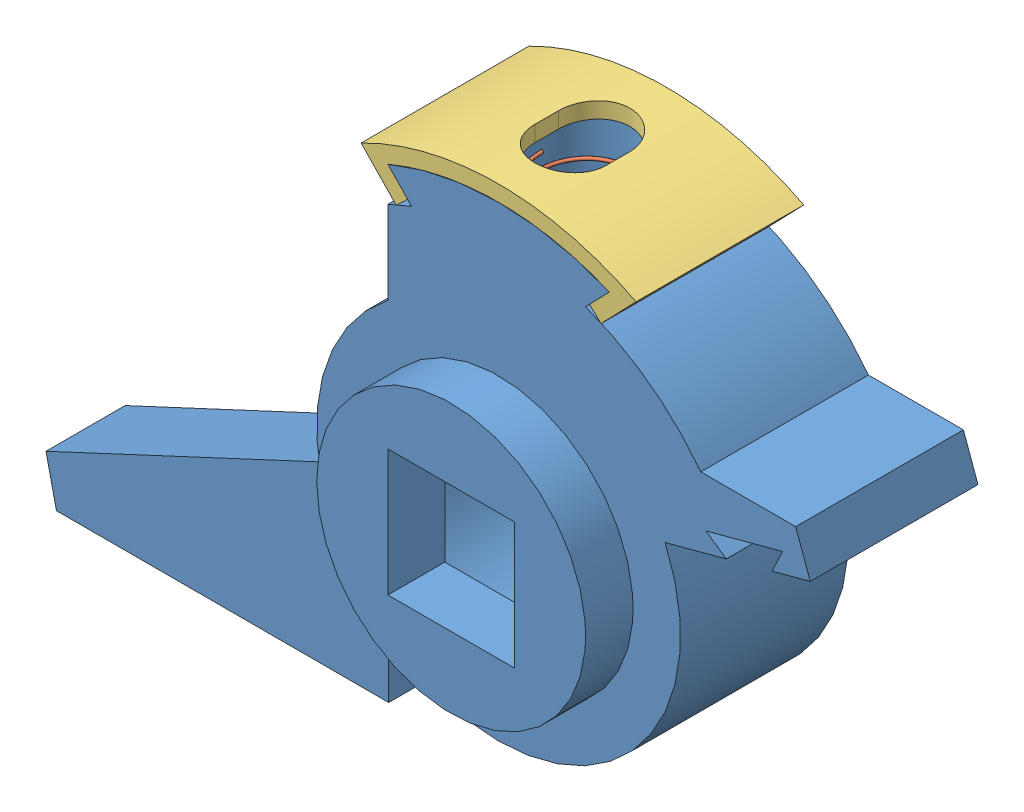
SolidWorks assembly noix int, configuration Défaut. Lengths in mm.
Overall size (52.31 35.86 13.6).
3 component instances, 3 part files, 4 mates.
Components (placement in the parent):
- noix interieure-1: noix interieure [Défaut] at origin size (52.31 34.86 13.6)
- ressort1-1: ressort1 [Défaut] at (0 11 0) x (-0.996138 0 -0.087798) z (0 1 0) size (5.8 6.7 9.79)
- Pièce15-1: Pièce15 [Défaut] at origin size (17.38 4.41 10.6)
Mates (geometry in assembly coordinates):
- Coïncidente1: coincident anti-aligned: axis of noix interieure-1 through (0 11 0) axis (0 1 0); line of ressort1-1 through (0 12.8205 0) axis (0 -1 0)
- Coïncidente2: coincident: plane of noix interieure-1 through (0 11 0) normal (0 1 0); point of ressort1-1
- Coaxiale2: concentric aligned: cylinder of noix interieure-1 through (0 0 5.3) axis (0 0 -1) radius 18; cylinder of Pièce15-1 through (0 0 5.3) axis (0 0 -1) radius 18
- Coïncidente3: coincident aligned: plane of noix interieure-1 through (0 0 -5.3) normal (0 0 -1); plane of Pièce15-1 through (0 0 -5.3) normal (0 0 -1)
